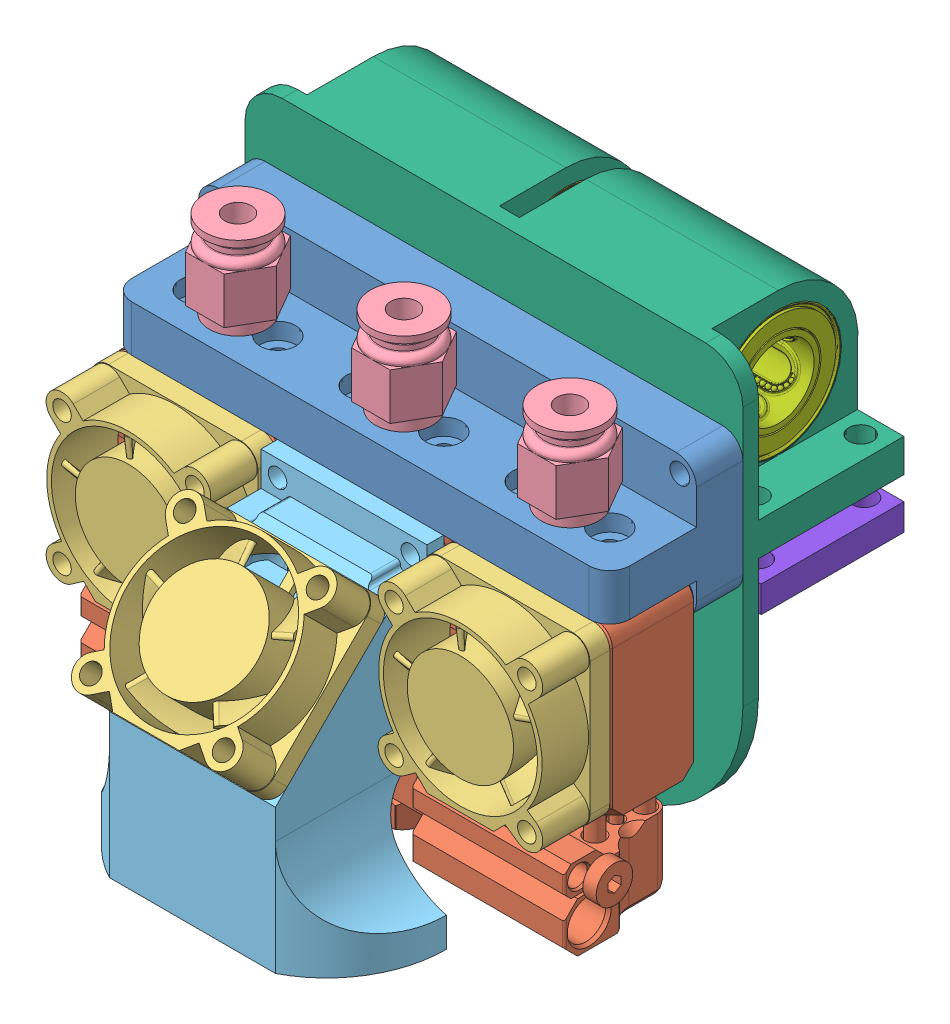
SolidWorks assembly TripleHotendAssembly, configuration Default. Lengths in mm.
Overall size (77 72.29 77.99).
16 component instances, 8 part files, 55 mates.
Components (placement in the parent):
- mosquito_triple_mount-1: mosquito_triple_mount [Default] at (30.6316 47.9573 50.1869) size (75 26 20.1)
- mosquito_model_to_publish-1: mosquito_model_to_publish [Default] at (5.6314 14.7193 63.7369) x (0 0 -1) z (1 0 0) size (18.85 47 27)
- mosquito_model_to_publish-2: mosquito_model_to_publish [Default] at (30.6314 14.7193 63.7369) x (0 0 1) z (-1 0 0) size (18.85 47 27)
- mosquito_model_to_publish-3: mosquito_model_to_publish [Default] at (55.6314 14.7193 63.7369) x (0 0 -1) z (1 0 0) size (18.85 47 27)
- fan 20mm-3: fan 20mm [Default] at (55.6314 30.7193 70.2369) size (25 25 10.01)
- PC4-M6-1: PC4-M6 [По умолчанию] at (5.6316 59.2073 63.7369) x (0 0 1) z (0 -1 0) size (10 11.55 18)
- PC4-M6-2: PC4-M6 [По умолчанию] at (30.6316 59.2073 63.7369) x (0.866025 0 -0.5) z (0 -1 0) size (10 11.55 18)
- PC4-M6-3: PC4-M6 [По умолчанию] at (55.6316 59.2073 63.7369) x (0.866025 0 -0.5) z (0 -1 0) size (10 11.55 18)
- mount+plate-4: mount+plate [Default] at (30.6314 30.7193 72.7769) x (-1 0 0) z (0 0 -1) size (44.45 44.5 26.71)
- fan 20mm-9: fan 20mm [Default] at (30.6314 29.2404 86.7558) x (1 0 0) z (0 0.707107 0.707107) size (25 25 10.01)
- fan 20mm-10: fan 20mm [Default] at (5.6314 30.7193 70.2369) size (25 25 10.01)
- triple_mount_adapter-1: triple_mount_adapter [Default] at (30.6316 47.9573 43.1869) size (75 65.5 24.33)
- 61205K760_FIXED ALIGNMENT LINEAR BALL BRNG-2: 61205K760_FIXED ALIGNMENT LINEAR BALL BRNG [61205K76] at (46.6316 55.9573 37.8529) x (0 0.407759 -0.913089) z (1 0 0) size (19 19 29)
- 61205K760_FIXED ALIGNMENT LINEAR BALL BRNG-3: 61205K760_FIXED ALIGNMENT LINEAR BALL BRNG [61205K76] at (14.6316 55.9573 37.8529) x (0 0.0015 0.999999) z (-1 0 0) size (19 19 29)
- 61205K760_FIXED ALIGNMENT LINEAR BALL BRNG-4: 61205K760_FIXED ALIGNMENT LINEAR BALL BRNG [61205K76] at (30.6316 14.4573 37.8529) x (0 0.554492 0.832189) z (-1 0 0) size (19 19 29)
- Belt_Clamp-1: Belt_Clamp [Default] at (30.6316 41.4573 25.947) size (75 4.5 21.5)
Mates (geometry in assembly coordinates):
- Coincident1: coincident aligned: plane of mosquito_triple_mount-1 through (30.6316 43.2193 50.1869) normal (0 -1 0); plane of mosquito_model_to_publish-1 through (5.6314 43.2193 57.2369) normal (0 -1 0)
- Concentric1: concentric aligned: cylinder of mosquito_triple_mount-1 through (11.6317 43.2193 63.7369) axis (0 1 0) radius 1.3498; cylinder of mosquito_model_to_publish-1 through (11.6314 43.2193 63.7369) axis (0 1 0) radius 1.025
- Concentric2: concentric aligned: cylinder of mosquito_triple_mount-1 through (-0.3686 43.2193 63.7369) axis (0 1 0) radius 1.3498; cylinder of mosquito_model_to_publish-1 through (-0.3686 43.2193 63.7369) axis (0 1 0) radius 1.025
- Coincident4: coincident aligned: plane of mosquito_triple_mount-1 through (30.6316 43.2193 50.1869) normal (0 -1 0); plane of mosquito_model_to_publish-2 through (30.6314 43.2193 70.2369) normal (0 -1 0)
- Concentric5: concentric aligned: cylinder of mosquito_triple_mount-1 through (24.6314 43.2193 63.7369) axis (0 1 0) radius 1.3498; cylinder of mosquito_model_to_publish-2 through (24.6314 43.2193 63.7369) axis (0 1 0) radius 1.025
- Concentric6: concentric aligned: cylinder of mosquito_triple_mount-1 through (36.6317 43.2193 63.7369) axis (0 1 0) radius 1.3498; cylinder of mosquito_model_to_publish-2 through (36.6314 43.2193 63.7369) axis (0 1 0) radius 1.025
- Coincident5: coincident aligned: plane of mosquito_triple_mount-1 through (30.6316 43.2193 50.1869) normal (0 -1 0); plane of mosquito_model_to_publish-3 through (55.6314 43.2193 57.2369) normal (0 -1 0)
- Concentric7: concentric aligned: cylinder of mosquito_triple_mount-1 through (61.6317 43.2193 63.7369) axis (0 1 0) radius 1.3498; cylinder of mosquito_model_to_publish-3 through (61.6314 43.2193 63.7369) axis (0 1 0) radius 1.025
- Concentric8: concentric aligned: cylinder of mosquito_triple_mount-1 through (49.6314 43.2193 63.7369) axis (0 1 0) radius 1.3498; cylinder of mosquito_model_to_publish-3 through (49.6314 43.2193 63.7369) axis (0 1 0) radius 1.025
- Coincident8: coincident aligned: plane of mosquito_model_to_publish-3 through (45.6314 40.7193 70.2369) normal (0 0 -1); plane of fan 20mm-3 through (55.6314 30.7193 70.2369) normal (0 0 -1)
- Concentric9: concentric aligned: cylinder of mosquito_model_to_publish-3 through (65.6314 40.7193 70.2369) axis (0 0 1) radius 1.4; cylinder of fan 20mm-3 through (65.6314 40.7193 70.2369) axis (0 0 1) radius 1.4
- Concentric11: concentric aligned: cylinder of mosquito_model_to_publish-3 through (45.6314 40.7193 70.2369) axis (0 0 1) radius 1.4; cylinder of fan 20mm-3 through (45.6314 40.7193 70.2369) axis (0 0 1) radius 1.4
- Coincident9: coincident anti-aligned: plane of mosquito_triple_mount-1 through (30.6316 50.2073 50.1869) normal (0 1 0); plane of PC4-M6-3 through (55.6316 50.2073 63.7369) normal (0 -1 0)
- Coincident10: coincident anti-aligned: plane of mosquito_triple_mount-1 through (30.6316 50.2073 50.1869) normal (0 1 0); plane of PC4-M6-2 through (30.6316 50.2073 63.7369) normal (0 -1 0)
- Coincident11: coincident anti-aligned: plane of mosquito_triple_mount-1 through (30.6316 50.2073 50.1869) normal (0 1 0); plane of PC4-M6-1 through (5.6316 50.2073 63.7369) normal (0 -1 0)
- Concentric16: concentric aligned: cylinder of mosquito_triple_mount-1 through (5.6316 43.2193 63.7369) axis (0 1 0) radius 2.5; cylinder of PC4-M6-1 through (5.6316 45.2073 63.7369) axis (0 1 0) radius 1.6
- Concentric17: concentric aligned: cylinder of mosquito_triple_mount-1 through (30.6316 43.2193 63.7369) axis (0 1 0) radius 2.5; cylinder of PC4-M6-2 through (30.6316 45.2073 63.7369) axis (0 1 0) radius 1.6
- Concentric18: concentric anti-aligned: cylinder of mosquito_triple_mount-1 through (55.6316 43.2193 63.7369) axis (0 1 0) radius 2.5; circle of PC4-M6-3
- Coincident21: coincident aligned: plane of mosquito_model_to_publish-2 through (40.6314 40.7193 70.2369) normal (0 0 -1); plane of mount+plate-4 through (30.6314 30.7193 70.2369) normal (0 0 -1)
- Concentric34: concentric aligned: cylinder of mosquito_model_to_publish-2 through (20.6314 40.7193 70.2369) axis (0 0 1) radius 1.4; cylinder of mount+plate-4 through (20.6314 40.7193 70.2369) axis (0 0 1) radius 1.4
- Concentric35: concentric aligned: cylinder of mosquito_model_to_publish-2 through (40.6314 40.7193 70.2369) axis (0 0 1) radius 1.4; cylinder of mount+plate-4 through (40.6314 40.7193 70.2369) axis (0 0 1) radius 1.4
- Coincident22: coincident anti-aligned: plane of mount+plate-4 through (30.6314 36.9693 79.0269) normal (0 0.707107 0.707107); plane of fan 20mm-9 through (30.6314 29.2404 86.7558) normal (0 -0.707107 -0.707107)
- Concentric36: concentric aligned: cylinder of mount+plate-4 through (20.6314 34.5155 77.8887) axis (0 0.707107 0.707107) radius 1.4; cylinder of fan 20mm-9 through (20.6314 36.3115 79.6847) axis (0 0.707107 0.707107) radius 1.4
- Coincident23: coincident aligned: circle of mount+plate-4; cylinder of fan 20mm-9 through (40.6314 36.3115 79.6847) axis (0 0.707107 0.707107) radius 1.4
- Coincident24: coincident aligned: plane of mosquito_model_to_publish-1 through (-4.3686 40.7193 70.2369) normal (0 0 -1); plane of fan 20mm-10 through (5.6314 30.7193 70.2369) normal (0 0 -1)
- Concentric37: concentric aligned: cylinder of mosquito_model_to_publish-1 through (-4.3686 40.7193 70.2369) axis (0 0 1) radius 1.4; cylinder of fan 20mm-10 through (-4.3686 40.7193 70.2369) axis (0 0 1) radius 1.4
- Concentric38: concentric aligned: cylinder of mosquito_model_to_publish-1 through (15.6314 40.7193 70.2369) axis (0 0 1) radius 1.4; cylinder of fan 20mm-10 through (15.6314 40.7193 70.2369) axis (0 0 1) radius 1.4
- Parallel3: parallel aligned: plane of mosquito_triple_mount-1 through (30.6316 43.2193 70.2869) normal (0 0 1); plane of PC4-M6-1 through (8.5183 52.2073 68.7369) normal (0 0 1)
- Parallel4: parallel aligned: plane of PC4-M6-1 through (8.5183 52.2073 68.7369) normal (0 0 1); plane of PC4-M6-2 through (33.5183 52.2073 68.7369) normal (0 0 1)
- Parallel5: parallel aligned: plane of PC4-M6-2 through (33.5183 52.2073 68.7369) normal (0 0 1); plane of PC4-M6-3 through (58.5183 52.2073 68.7369) normal (0 0 1)
- Coincident29: coincident anti-aligned: plane of mosquito_triple_mount-1 through (55.6316 37.4573 50.1869) normal (0 0 -1); plane of triple_mount_adapter-1 through (55.6316 37.4573 50.1869) normal (0 0 1)
- Coincident30: coincident aligned: plane of mosquito_triple_mount-1 through (68.1316 37.4573 57.1869) normal (1 0 0); plane of triple_mount_adapter-1 through (68.1316 37.4573 50.1869) normal (1 0 0)
- Concentric39: concentric aligned: cylinder of mosquito_triple_mount-1 through (55.6316 37.4573 57.1869) axis (0 0 -1) radius 1.7999; cylinder of triple_mount_adapter-1 through (55.6316 37.4573 50.1869) axis (0 0 -1) radius 1.7999
- Concentric40: concentric anti-aligned: cylinder of triple_mount_adapter-1 through (32.1316 55.9573 37.8529) axis (1 0 0) radius 9.5; cylinder of 61205K760_FIXED ALIGNMENT LINEAR BALL BRNG-2 through (61.1316 55.9573 37.8529) axis (-1 0 0) radius 9.5
- Coincident31: coincident aligned: plane of triple_mount_adapter-1 through (61.1316 47.9573 43.1869) normal (1 0 0); plane of 61205K760_FIXED ALIGNMENT LINEAR BALL BRNG-2 through (61.1316 55.9573 37.8529) normal (1 0 0)
- Concentric41: concentric anti-aligned: cylinder of triple_mount_adapter-1 through (29.1316 55.9573 37.8529) axis (-1 0 0) radius 9.5; cylinder of 61205K760_FIXED ALIGNMENT LINEAR BALL BRNG-3 through (0.1316 55.9573 37.8529) axis (1 0 0) radius 9.5
- Coincident32: coincident aligned: plane of triple_mount_adapter-1 through (0.1316 47.9573 43.1869) normal (-1 0 0); plane of 61205K760_FIXED ALIGNMENT LINEAR BALL BRNG-3 through (0.1316 55.9573 37.8529) normal (-1 0 0)
- Concentric43: concentric anti-aligned: cylinder of triple_mount_adapter-1 through (45.1316 14.4573 37.8529) axis (-1 0 0) radius 9.5; cylinder of 61205K760_FIXED ALIGNMENT LINEAR BALL BRNG-4 through (16.1316 14.4573 37.8529) axis (1 0 0) radius 9.5
- Coincident35: coincident aligned: plane of triple_mount_adapter-1 through (45.1316 14.4573 37.8529) normal (1 0 0); plane of 61205K760_FIXED ALIGNMENT LINEAR BALL BRNG-4 through (45.1316 14.4573 37.8529) normal (1 0 0)
- Concentric44: concentric aligned: cylinder of triple_mount_adapter-1 through (32.1316 55.9573 37.8529) axis (1 0 0) radius 12; cylinder of 61205K760_FIXED ALIGNMENT LINEAR BALL BRNG-2 through (32.1316 55.9573 37.8529) axis (1 0 0) radius 5.3846
- Concentric45: concentric aligned: cylinder of triple_mount_adapter-1 through (29.1316 55.9573 37.8529) axis (-1 0 0) radius 12; circle of 61205K760_FIXED ALIGNMENT LINEAR BALL BRNG-3
- Concentric46: concentric aligned: cylinder of triple_mount_adapter-1 through (45.1316 14.4573 37.8529) axis (-1 0 0) radius 12; cylinder of 61205K760_FIXED ALIGNMENT LINEAR BALL BRNG-4 through (45.1316 14.4573 37.8529) axis (-1 0 0) radius 5.3846
- Concentric47: concentric aligned: circle of triple_mount_adapter-1; circle of Triple_mount_boss-1
- Concentric48: concentric anti-aligned: circle of triple_mount_adapter-1; circle of Triple_mount_boss-2
- Concentric49: concentric aligned: circle of triple_mount_adapter-1; circle of Triple_mount_boss-3
- Concentric50: concentric anti-aligned: circle of triple_mount_adapter-1; circle of Triple_mount_boss-4
- Concentric51: concentric anti-aligned: circle of triple_mount_adapter-1; circle of Triple_mount_boss-6
- Coincident41: coincident anti-aligned: plane of triple_mount_adapter-1 through (30.6316 47.9573 47.8529) normal (0 0 -1); plane of Triple_mount_boss-4 through (6.1316 26.9573 47.8529) normal (0 0 1)
- Coincident42: coincident anti-aligned: plane of triple_mount_adapter-1 through (30.6316 47.9573 47.8529) normal (0 0 -1); plane of Triple_mount_boss-3 through (18.1316 33.9573 47.8529) normal (0 0 1)
- Coincident43: coincident anti-aligned: plane of triple_mount_adapter-1 through (30.6316 47.9573 47.8529) normal (0 0 -1); plane of Triple_mount_boss-6 through (30.6316 33.9573 47.8529) normal (0 0 1)
- Coincident44: coincident anti-aligned: plane of triple_mount_adapter-1 through (30.6316 47.9573 47.8529) normal (0 0 -1); plane of Triple_mount_boss-1 through (43.1316 33.9573 47.8529) normal (0 0 1)
- Coincident45: coincident anti-aligned: plane of triple_mount_adapter-1 through (30.6316 47.9573 47.8529) normal (0 0 -1); plane of Triple_mount_boss-2 through (55.1316 26.9573 47.8529) normal (0 0 1)
- Distance1: distance = 1.5 mm: point of Belt_Clamp-1; unknown of triple_mount_adapter-1
- Width1: width aligned: plane of triple_mount_adapter-1 through (-6.8684 37.4573 50.1869) normal (-1 0 0); plane of Belt_Clamp-1 through (68.1316 37.4573 50.1869) normal (1 0 0); plane of triple_mount_adapter-1 through (-6.8684 41.4573 47.447) normal (-1 0 0); plane of Belt_Clamp-1 through (68.1316 41.4573 47.447) normal (1 0 0)
- Coincident48: coincident aligned: plane of triple_mount_adapter-1 through (29.1316 47.9573 25.947) normal (0 0 -1); plane of Belt_Clamp-1 through (30.6316 41.4573 25.947) normal (0 0 -1)
